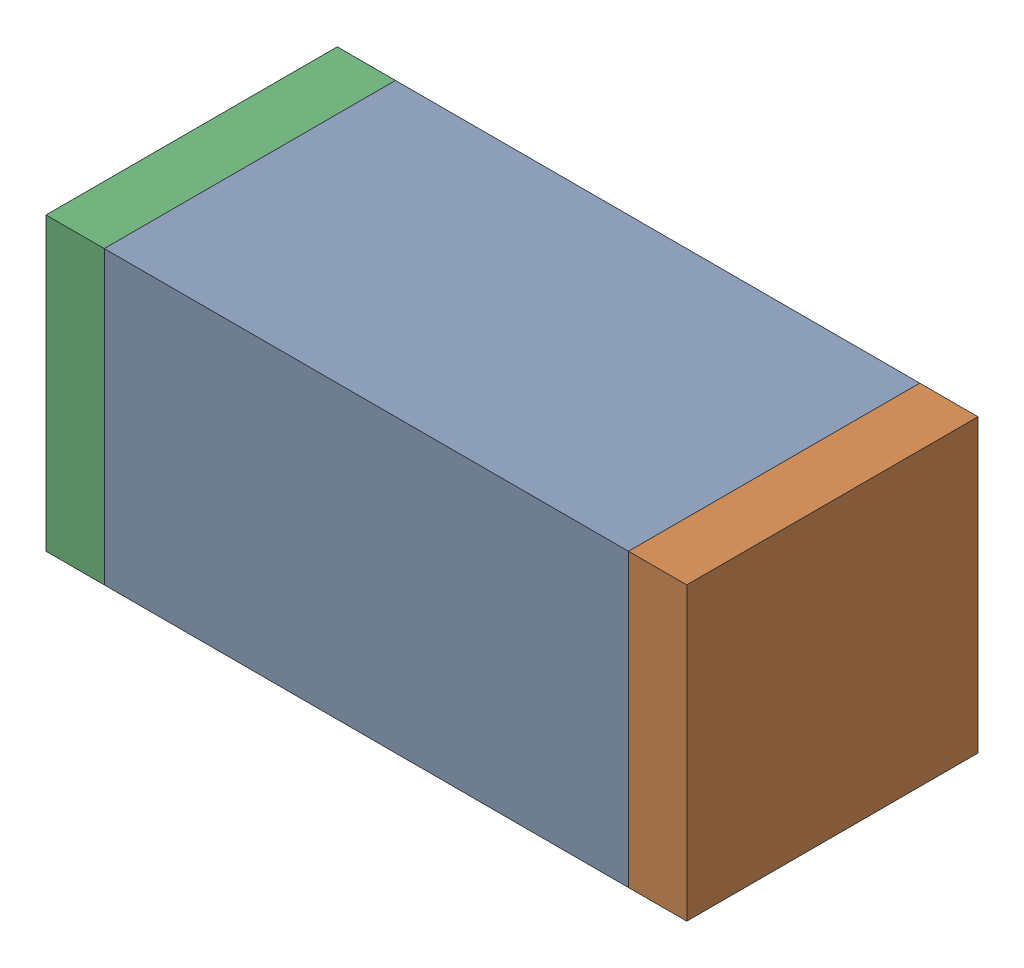
SolidWorks assembly C65, configuration Default. Lengths in mm.
Overall size (1.1 0.5 0.5).
6 component instances, 2 part files, 0 mates.
Components (placement in the parent):
- 836749680-1: 836749680 [Default] at (121.15 54.4 0) size (0.9 0.5 0.5)
  - Extruded_4-1: Extruded_4 [Default] at origin size (0.9 0.5 0.5)
- 810156080-1: 810156080 [Default] at (121.65 54.4 0) size (0.1 0.5 0.5)
  - Extruded_5-1: Extruded_5 [Default] at origin size (0.1 0.5 0.5)
- 810156080-2: 810156080 [Default] at (120.65 54.4 0) size (0.1 0.5 0.5)
  - Extruded_5-1: Extruded_5 [Default] at origin size (0.1 0.5 0.5)
